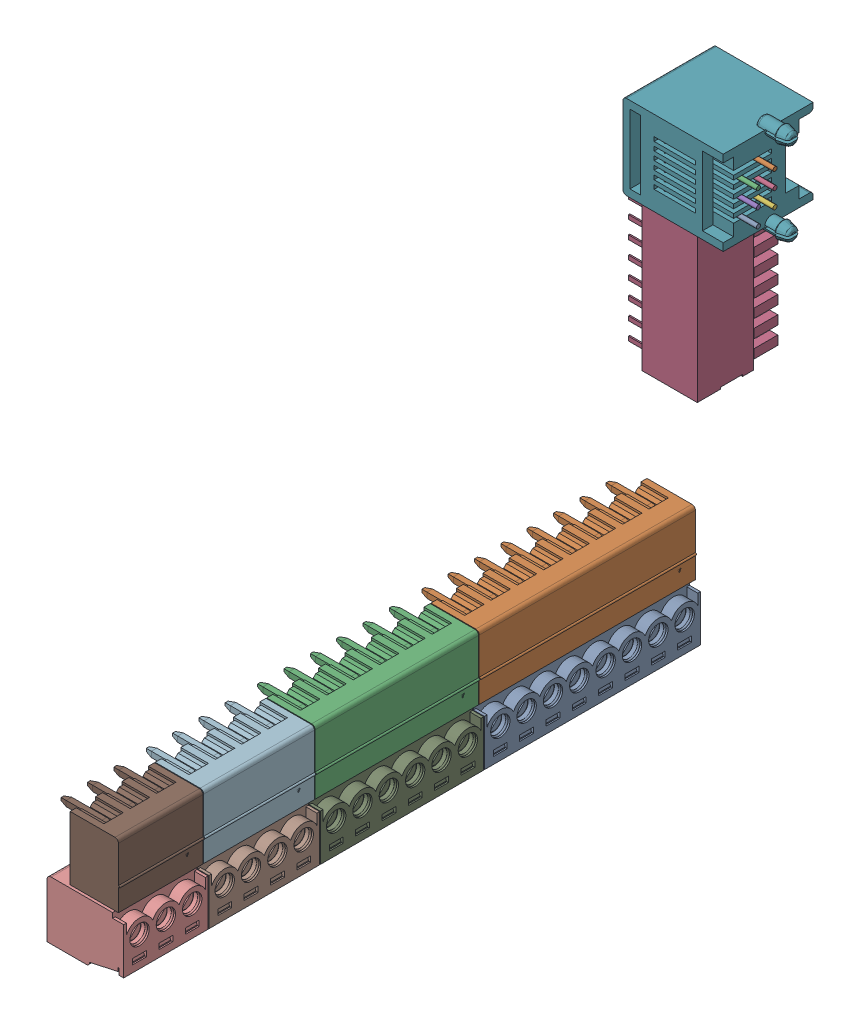
SolidWorks assembly Component7, configuration Component7. Lengths in mm.
Overall size (19.6 67.18 94.5).
17 component instances, 16 part files, 0 mates.
Components (placement in the parent):
- RJ12 v2-1: RJ12 v2 [RJ12 v2] at origin size (17.7 14.34 13)
  - Fusion011-1: Fusion011 [Fusion011] at (21.75 14.2 -49.5) x (0 -1 0) z (-1 0 0) size (0.6 8.66 11.78)
  - Fusion010-1: Fusion010 [Fusion010] at (21.75 21.4 -49.5) x (0 -1 0) z (-1 0 0) size (0.6 8.66 11.78)
  - Fusion009-1: Fusion009 [Fusion009] at (21.75 19 -49.5) x (0 -1 0) z (-1 0 0) size (0.6 8.66 11.78)
  - Fusion008-1: Fusion008 [Fusion008] at (21.75 19 -49.5) x (0 -1 0) z (-1 0 0) size (0.6 8.66 11.78)
  - Fusion007-1: Fusion007 [Fusion007] at (21.75 16.6 -49.5) x (0 -1 0) z (-1 0 0) size (0.6 8.66 11.78)
  - Fusion006-1: Fusion006 [Fusion006] at (21.75 16.6 -49.5) x (0 -1 0) z (-1 0 0) size (0.6 8.66 11.78)
  - Fusion005-1: Fusion005 [Fusion005] at (21.75 16.6 -49.5) x (0 -1 0) z (-1 0 0) size (14.34 13 17.7)
- 15EDGK-3.81-04P-14-00AH v1-1: 15EDGK-3.81-04P-14-00AH v1 [15EDGK-3.81-04P-14-00AH v1] at (5.4 -27.8 16.65) x (0 0 1) z (1 0 0) size (16.03 15.6 11.1)
- 15EDGK-3.81-06P-14-00AH v1-1: 15EDGK-3.81-06P-14-00AH v1 [15EDGK-3.81-06P-14-00AH v1] at (5.4 -27.8 -7.1) x (0 0 1) z (1 0 0) size (23.65 15.6 11.1)
- 15EDGK-3.81-03P-14-00AH v1-1: 15EDGK-3.81-03P-14-00AH v1 [15EDGK-3.81-03P-14-00AH v1] at (5.4 -27.8 32.78) x (0 0 1) z (1 0 0) size (12.22 15.6 11.1)
- 15EDGRC-3.81-03P-14-00AH v1-1: 15EDGRC-3.81-03P-14-00AH v1 [15EDGRC-3.81-03P-14-00AH v1] at (8.75 -25.4 32.78) x (0 0 1) z (1 0 0) size (12.22 9.2 10.6)
- 15EDGRC-3.81-04P-14-00AH v1-1: 15EDGRC-3.81-04P-14-00AH v1 [15EDGRC-3.81-04P-14-00AH v1] at (8.75 -25.4 16.65) x (0 0 1) z (1 0 0) size (16.03 9.2 10.6)
- 15EDGK-3.81-08P-14-00AH v1-1: 15EDGK-3.81-08P-14-00AH v1 [15EDGK-3.81-08P-14-00AH v1] at (5.4 -27.8 -38.47) x (0 0 1) z (1 0 0) size (31.27 15.6 11.1)
- 15EDGRC-3.81-08P-14-00AH v1-1: 15EDGRC-3.81-08P-14-00AH v1 [15EDGRC-3.81-08P-14-00AH v1] at (8.75 -25.4 -38.47) x (0 0 1) z (1 0 0) size (31.27 9.2 10.6)
- 15EDGRC-3.81-06P-14-00AH v1-1: 15EDGRC-3.81-06P-14-00AH v1 [15EDGRC-3.81-06P-14-00AH v1] at (8.75 -25.4 -7.1) x (0 0 1) z (1 0 0) size (23.65 9.2 10.6)
- DS1040-08RT v1-1: DS1040-08RT v1 [DS1040-08RT v1] at (8.9 -0.51 -42.55) x (0 1 0) z (1 0 0) size (21.78 11.7 11)
